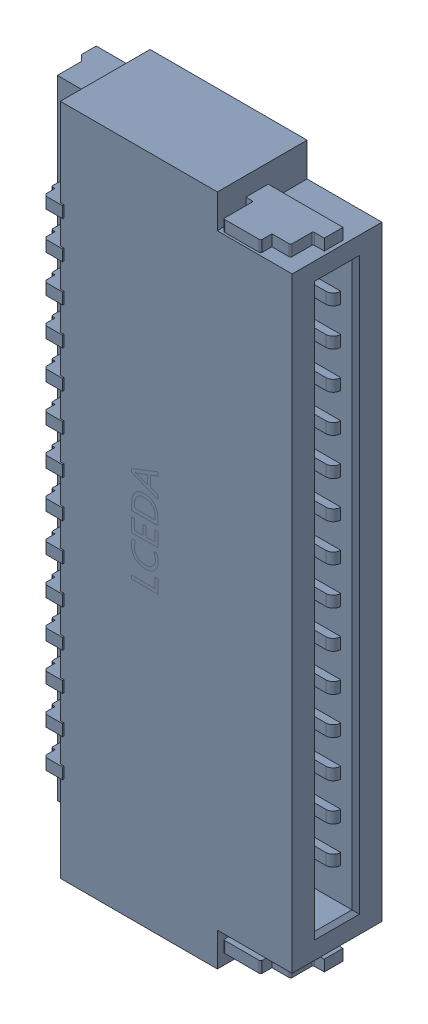
SolidWorks assembly FPC3, configuration Défaut. Lengths in mm.
Overall size (3.8 9 1.23).
4 component instances, 1 part files, 0 mates.
Components (placement in the parent):
- FH34SRJ-14S-0.5SH(50)-1: FH34SRJ-14S-0.5SH(50) [Défaut] at (70.8901 -26.4408 -0.4818) x (0 -1 0) z (0 0 -1) size (9 3.8 1.23)
  - FPC1.step-1: FPC1.step [Défaut] at (8.84 -9.4501 1.6001) size (9 3.8 1.23)
    - FFC-SMD_14P-P0.50_FH34SRJ-14S-0.5SH.step-1: FFC-SMD_14P-P0.50_FH34SRJ-14S-0.5SH.step [Défaut] at origin size (9 3.8 1.23)
      - SOLID.step-1: SOLID.step [Défaut] at origin size (9 3.8 1.23)
